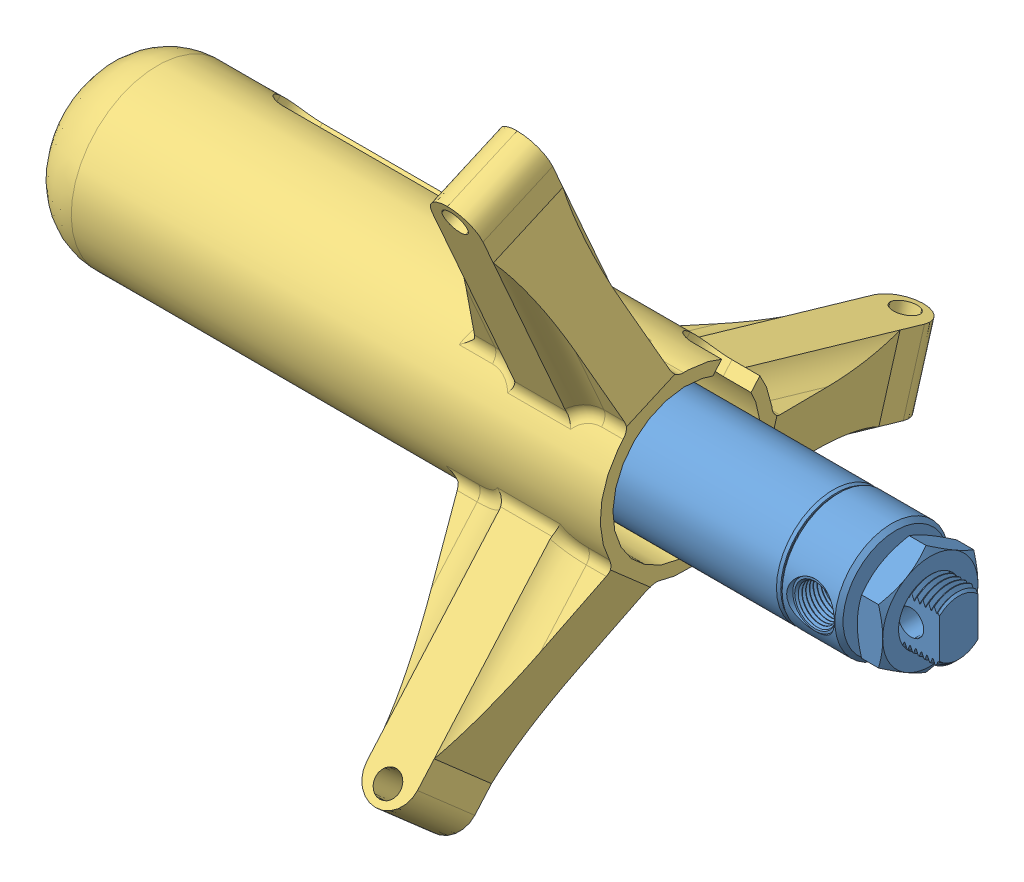
SolidWorks assembly Piston Assem, configuration Default. Lengths in mm.
Overall size (219.57 190.3 193.1).
3 component instances, 3 part files, 4 mates.
Components (placement in the parent):
- Piston Body-1: Piston Body [6498K654] at (48.3607 91.1672 114.2196) size (153.11 28.45 28.45)
- Piston Shaft-1: Piston Shaft [6498K654] at (-2.4393 91.1672 114.2196) x (1 0 0) z (0 0.581675 -0.813421) size (70.22 8.18 8.17)
- Piston Cup CORRECT-2: Piston Cup CORRECT [Default] at (-83.3383 91.1672 114.2196) x (0 -0.658665 -0.752436) z (0 -0.752436 0.658665) size (150.78 147.64 120.93)
Mates (geometry in assembly coordinates):
- Concentric1: concentric: circle of Piston Body-1; cylinder of Piston Shaft-1 through (-73.8133 91.1672 114.2196) axis (-1 0 0) radius 3.9624
- LimitDistance1: limit distance = 66.548 mm: plane of Piston Body-1 through (-19.9653 91.1672 114.2196) normal (-1 0 0); plane of Piston Shaft-1 through (-86.5133 94.3955 116.5281) normal (-1 0 0)
- Concentric4: concentric: circle of Piston Shaft-1; circle of Piston Cup CORRECT-2
- Distance1: distance = 3.175 mm: plane of Piston Cup CORRECT-2 through (-83.3383 91.1672 114.2196) normal (-1 0 0); plane of Piston Shaft-1 through (-86.5133 94.3955 116.5281) normal (-1 0 0)
